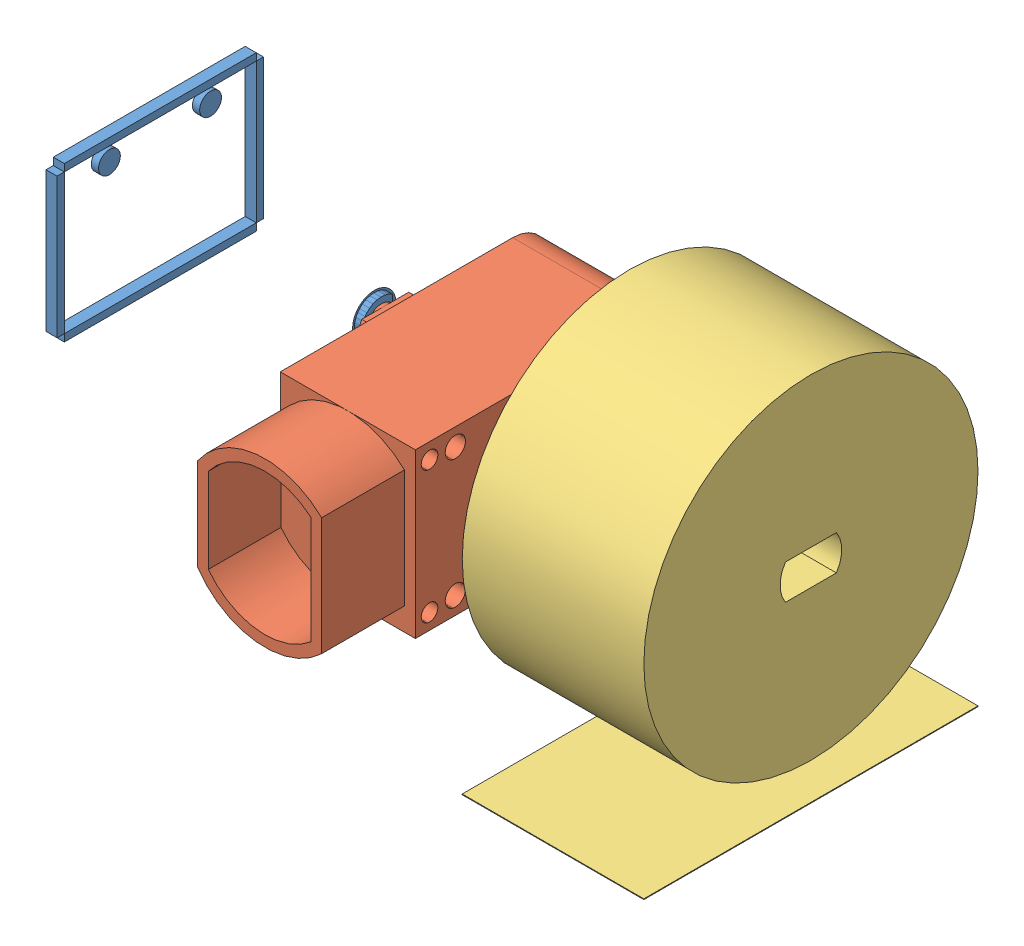
SolidWorks assembly Assem2, configuration Default. Lengths in mm.
Overall size (88.58 51.1 58.85).
3 component instances, 3 part files, 10 mates.
Components (placement in the parent):
- Rotary_Encorder_Holder-1: Rotary_Encorder_Holder [Default] at (-68.578 -140.5415 -117.7314) x (0 0 1) z (1 0 0) size (28.42 21.28 29.48)
- Robot Wheel Motor Mount-1: Robot Wheel Motor Mount [Default] at (-28.6 22.5 42) x (0 0 -1) z (1 0 0) size (53.4 22.5 40.1)
- Part1^Assem2-1: Part1^Assem2 [Default] at (-10 22.5 42) x (0 0 -1) z (1 0 0) size (46 51.1 25) (virtual)
Mates (geometry in assembly coordinates):
- Concentric1: concentric anti-aligned: cylinder of Rotary_Encorder_Holder-1 through (-40.1 11.25 17.55) axis (-1 0 0) radius 2.9813; cylinder of Robot Wheel Motor Mount-1 through (-40.1 11.25 17.55) axis (1 0 0) radius 1.9003
- Coincident41: coincident anti-aligned: plane of Rotary_Encorder_Holder-1 through (-40.1 11.25 17.55) normal (1 0 0); plane of Robot Wheel Motor Mount-1 through (-40.1 11.25 17.55) normal (-1 0 0)
- Parallel22: parallel aligned: plane of Rotary_Encorder_Holder-1 through (-68.578 2.4585 -117.7314) normal (0 -1 0); plane of Robot Wheel Motor Mount-1 through (-10 0 42) normal (0 -1 0)
- Coincident42: coincident anti-aligned: plane of Robot Wheel Motor Mount-1 through (-28.6 22.5 0) normal (0 0 -1)
- Coincident43: coincident anti-aligned: plane of Robot Wheel Motor Mount-1 through (-10 0 42) normal (0 -1 0)
- Coincident44: coincident aligned: plane of Robot Wheel Motor Mount-1 through (0 5 10) normal (1 0 0)
- InPlace1: in place: plane of Robot Wheel Motor Mount-1 through (-10 5 10) normal (1 0 0); plane of ? through (-10 0 0) normal (1 0 0); moOrthogonalPlaneRef_w of Robot Wheel Motor Mount-1 through (-10 5 10) normal (1 0 0); plane of ? through (-10 0 0) normal (0 1 0); plane of Robot Wheel Motor Mount-1 through (-10 5 10) normal (1 0 0); plane of ? through (-10 0 0) normal (0 0 -1); plane of Robot Wheel Motor Mount-1 through (-10 5 10) normal (1 0 0); unknown of Part1^Assem2-1
- Coincident45: coincident aligned: plane of Robot Wheel Motor Mount-1; plane of Part1^Assem2-1
- Coincident46: coincident aligned: moOrthogonalPlaneRef_w of Robot Wheel Motor Mount-1 through (-10 22.5 42) normal (0 1 0); plane of Part1^Assem2-1 through (-10 22.5 42) normal (0 1 0)
- Coincident47: coincident anti-aligned: moOrthogonalPlaneRef_w of Robot Wheel Motor Mount-1 through (-10 22.5 42) normal (0 0 1); plane of Part1^Assem2-1 through (-10 22.5 42) normal (0 0 -1)
